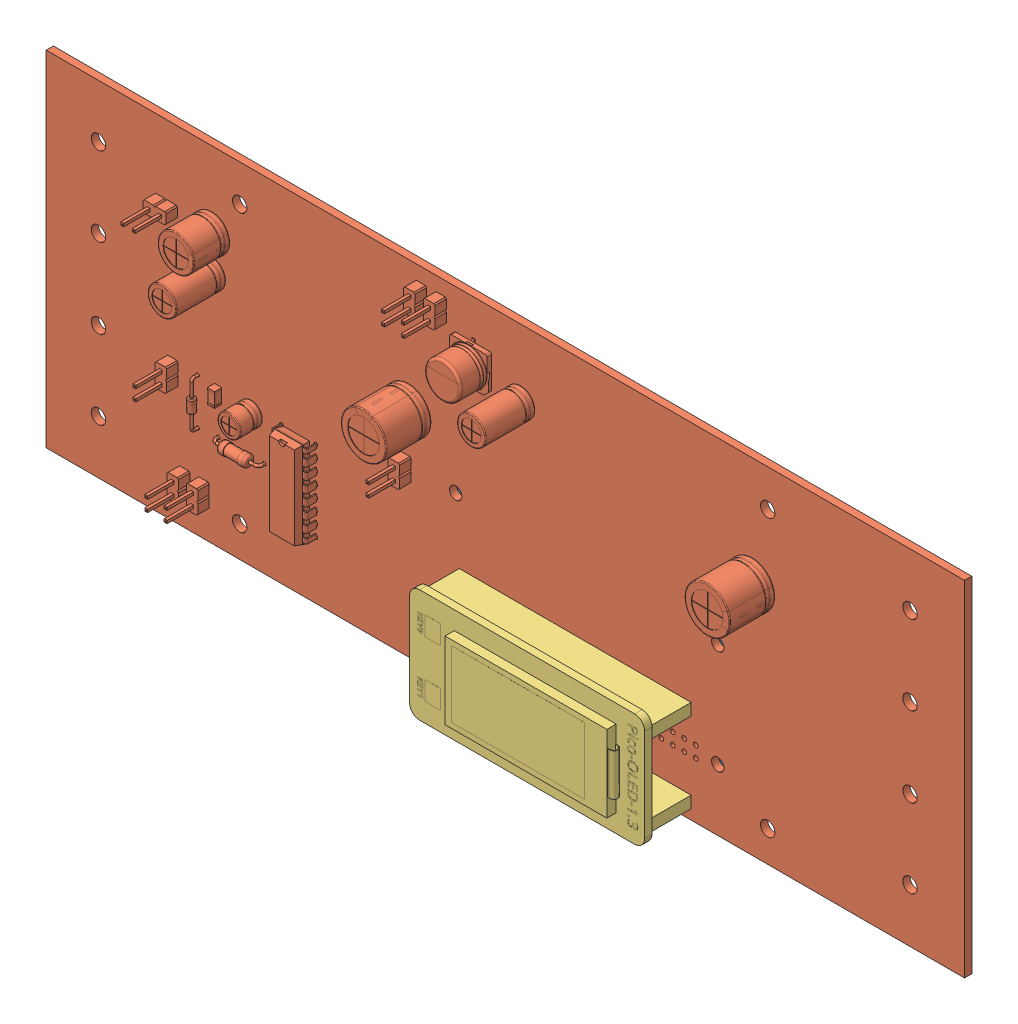
SolidWorks assembly Assem2, configuration Default. Lengths in mm.
Overall size (203.2 76.2 22).
3 component instances, 3 part files, 7 mates.
Components (placement in the parent):
- Raspberry Pi Zero 2 W-1: Raspberry Pi Zero 2 W [Default] at (-105.6109 -56.9615 172.8335) x (1 0 0) z (0 1 0) size (65.8 5.05 30.58)
- SeniorDesignPCB11182023-1: SeniorDesignPCB11182023 [Default] at (-225.2079 -5.8985 173.6335) size (203.2 76.2 14.3)
- Pico-OLED-1.3.step-1: Pico-OLED-1.3.step [Default] at (-131.5653 -79.7433 188.4735) size (52 25 12.76)
Mates (geometry in assembly coordinates):
- Coincident1: coincident anti-aligned: plane of Raspberry Pi Zero 2 W-1 through (-105.6109 -56.9615 173.6335) normal (0 0 1); plane of SeniorDesignPCB11182023-1 through (-123.6079 -43.9985 173.6335) normal (0 0 -1)
- Concentric1: concentric anti-aligned: cylinder of Raspberry Pi Zero 2 W-1 through (-76.6109 -68.4615 172.0335) axis (0 0 -1) radius 1.35; circle of SeniorDesignPCB11182023-1
- Concentric2: concentric aligned: circle of Raspberry Pi Zero 2 W-1; cylinder of SeniorDesignPCB11182023-1 through (-76.6109 -68.4615 172.8335) axis (0 0 1) radius 1.375
- Lock1: lock: unknown of Raspberry Pi Zero 2 W-1; unknown of SeniorDesignPCB11182023-1
- Lock2: lock: unknown of Raspberry Pi Zero 2 W-1; unknown of SeniorDesignPCB11182023-1
- Coincident3: coincident: plane of SeniorDesignPCB11182023-1 through (-103.0339 -76.0533 177.8235) normal (0 0 1); plane of Pico-OLED-1.3.step-1 through (-108.2452 -52.7696 177.8235) normal (0 0 -1)
- Coincident4: coincident aligned: line of SeniorDesignPCB11182023-1 through (-110.3999 -77.3233 177.8235) axis (1 0 0); line of Pico-OLED-1.3.step-1 through (-131.2153 -77.3233 177.8235) axis (1 0 0)
